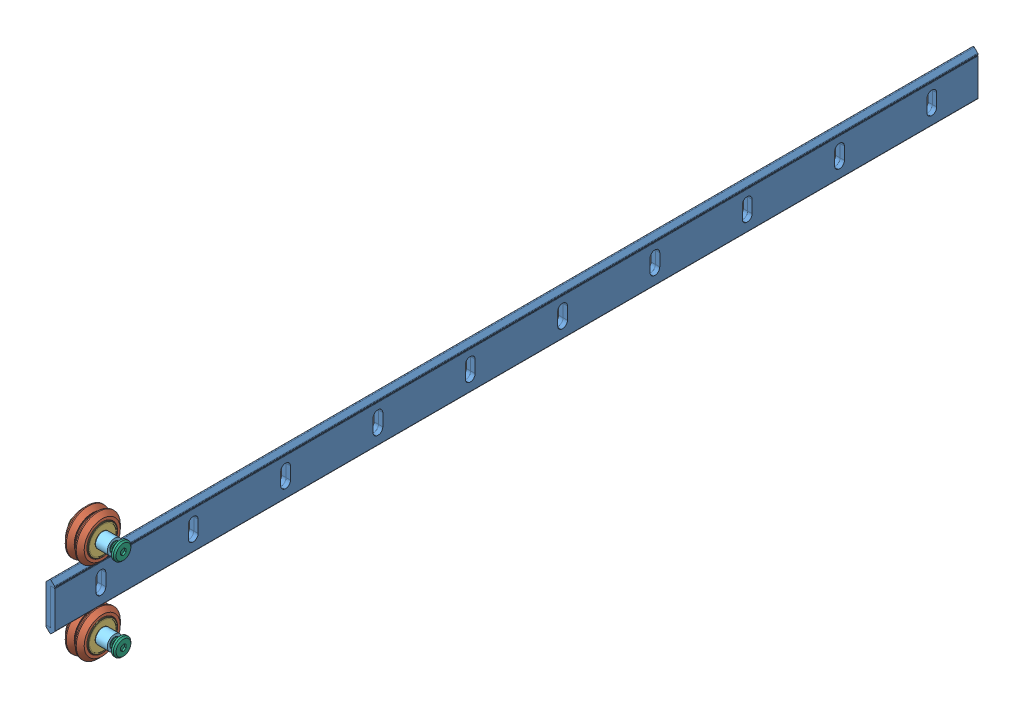
SolidWorks assembly Open Rail Back to Back 20mm with Wheels, configuration Default. Lengths in mm.
Overall size (27.2 68.89 500).
18 component instances, 7 part files, 9 mates.
Components (placement in the parent):
- Open Rail 500mm-1: Open Rail 500mm [Default] at (-38.0346 -0.3247 -238.6044) size (4.75 22.5 500)
- Open Rail 500mm-2: Open Rail 500mm [Default] at (-33.2846 19.2044 -238.6044) x (-1 0 0) z (0 0 1) size (4.75 22.5 500)
- V-Slot Delrin Dual Wheel Assembly-1: V-Slot Delrin Dual Wheel Assembly [Default] at (-24.575 -26.0964 242.6071) x (0 0 -1) z (1 0 0) size (23.89 23.89 27.2)
  - Delrin Dual V-Wheel-1: Delrin Dual V-Wheel [Default] at (4.1766 13.0717 -11.0846) size (23.89 23.89 10.23)
  - Precision Ball Bearing-1: Precision Ball Bearing [Default] at (4.1766 13.0717 -8.0846) x (0 0 -1) z (1 0 0) size (5 16 16)
  - Precision Ball Bearing-2: Precision Ball Bearing [Default] at (4.1766 13.0717 -14.0846) x (0 0 -1) z (1 0 0) size (5 16 16)
  - 5mm Precision Washer-1: 5mm Precision Washer [Default] at (4.1766 13.0717 -11.5846) x (0 0 1) z (-1 0 0) size (1 10 10)
  - .25 Inch Aluminum Spacer-1: .25 Inch Aluminum Spacer [Default] at (4.1766 13.0717 0.7654) x (0 0 -1) z (1 0 0) size (6.35 8 8)
  - 5mm Low Profile Socket Head Screw - Multiple Lengths-1: 5mm Low Profile Socket Head Screw - Multiple Lengths [Default] at (4.1766 13.0717 5.5154) x (0 0 -1) z (1 0 0) size (27.2 9.5 9.5)
  - Nylon Insert Hex Locknut 5mm-1: Nylon Insert Hex Locknut 5mm [Default] at (4.1766 13.0717 -16.5846) x (-0.923728 -0.383049 0) z (0 0 -1) size (7.68 8.82 4.5)
- V-Slot Delrin Dual Wheel Assembly-2: V-Slot Delrin Dual Wheel Assembly [Default] at (-24.575 18.9036 242.6071) x (0 0 -1) z (1 0 0) size (23.89 23.89 27.2)
  - Delrin Dual V-Wheel-1: Delrin Dual V-Wheel [Default] at (4.1766 13.0717 -11.0846) size (23.89 23.89 10.23)
  - Precision Ball Bearing-1: Precision Ball Bearing [Default] at (4.1766 13.0717 -8.0846) x (0 0 -1) z (1 0 0) size (5 16 16)
  - Precision Ball Bearing-2: Precision Ball Bearing [Default] at (4.1766 13.0717 -14.0846) x (0 0 -1) z (1 0 0) size (5 16 16)
  - 5mm Precision Washer-1: 5mm Precision Washer [Default] at (4.1766 13.0717 -11.5846) x (0 0 1) z (-1 0 0) size (1 10 10)
  - .25 Inch Aluminum Spacer-1: .25 Inch Aluminum Spacer [Default] at (4.1766 13.0717 0.7654) x (0 0 -1) z (1 0 0) size (6.35 8 8)
  - 5mm Low Profile Socket Head Screw - Multiple Lengths-1: 5mm Low Profile Socket Head Screw - Multiple Lengths [Default] at (4.1766 13.0717 5.5154) x (0 0 -1) z (1 0 0) size (27.2 9.5 9.5)
  - Nylon Insert Hex Locknut 5mm-1: Nylon Insert Hex Locknut 5mm [Default] at (4.1766 13.0717 -16.5846) x (-0.923728 -0.383049 0) z (0 0 -1) size (7.68 8.82 4.5)
Mates (geometry in assembly coordinates):
- Coincident1: coincident anti-aligned: plane of Open Rail 500mm-1 through (-35.6596 -0.3247 261.3956) normal (1 0 0); plane of Open Rail 500mm-2 through (-35.6596 19.2044 261.3956) normal (-1 0 0)
- Coincident2: coincident anti-aligned: plane of Open Rail 500mm-1 through (-38.0346 -0.3247 261.3956) normal (0 -1 0); plane of Open Rail 500mm-2 through (-35.6596 -0.3247 261.3956) normal (0 1 0)
- Coincident3: coincident aligned: plane of Open Rail 500mm-1 through (-35.6596 21.6697 261.3956) normal (0 0 1); plane of Open Rail 500mm-2 through (-35.6596 -2.7899 261.3956) normal (0 0 1)
- Coincident4: coincident aligned: line of Open Rail 500mm-2 through (-35.6596 18.9028 261.3956) axis (0 -1 0); plane of V-Slot Delrin Dual Wheel Assembly-1/Delrin Dual V-Wheel-1 through (-35.6596 -13.0247 238.4305) normal (1 0 0)
- Distance1: distance = 12.7 mm aligned: plane of V-Slot Delrin Dual Wheel Assembly-1/Delrin Dual V-Wheel-1; plane of Open Rail 500mm-1 through (-38.0346 -0.3247 -238.6044) normal (0 1 0)
- Coincident7: coincident aligned: line of Open Rail 500mm-2 through (-35.6596 18.9028 261.3956) axis (0 -1 0); plane of V-Slot Delrin Dual Wheel Assembly-2/Delrin Dual V-Wheel-1 through (-35.6596 32.0753 238.4305) normal (1 0 0)
- Distance2: distance = 32.3 mm aligned: plane of Open Rail 500mm-1 through (-38.0346 -0.3247 -238.6044) normal (0 1 0); plane of V-Slot Delrin Dual Wheel Assembly-2/Delrin Dual V-Wheel-1
- Coincident12: coincident aligned: plane of V-Slot Delrin Dual Wheel Assembly-1/Delrin Dual V-Wheel-1 through (-35.6596 -13.0247 238.4305) normal (1 0 0); plane of V-Slot Delrin Dual Wheel Assembly-2/Delrin Dual V-Wheel-1 through (-35.6596 32.0753 238.4305) normal (1 0 0)
- Coincident13: coincident aligned: plane of V-Slot Delrin Dual Wheel Assembly-1/Delrin Dual V-Wheel-1 through (-35.6596 -13.0247 238.4305) normal (0 0 -1); plane of V-Slot Delrin Dual Wheel Assembly-2/Delrin Dual V-Wheel-1 through (-35.6596 32.0753 238.4305) normal (0 0 -1)
